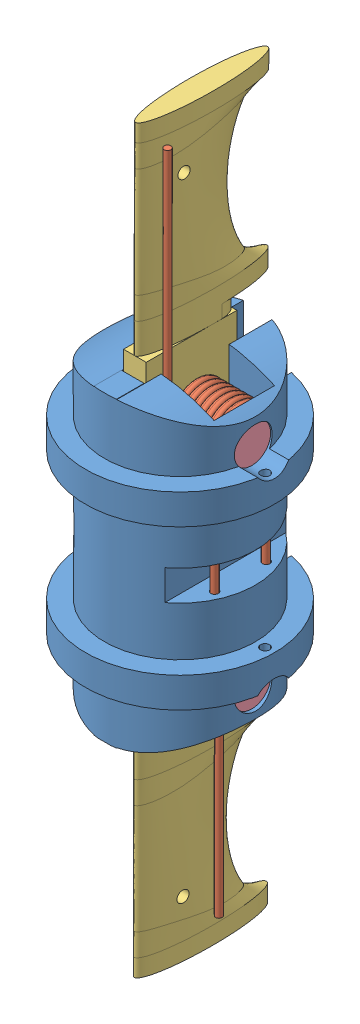
SolidWorks assembly Сборка управления 3, configuration Default. Lengths in mm.
Overall size (25 97.92 24.75).
7 component instances, 4 part files, 14 mates.
Components (placement in the parent):
- Ось Рулей 2-1: Ось Рулей 2 [Default] at (11.2417 23.0929 31.1428) size (25 40 24.75)
- Пружина 1-1: Пружина 1 [Default] at (16.1032 37.0366 31.1428) x (1 0 0) z (0 -1 0) size (7.17 7.86 53.5)
- Пружина 1-2: Пружина 1 [Default] at (16.1032 9.1492 31.1428) x (1 0 0) z (0 1 0) size (7.17 7.86 53.5)
- Плоскость 3-1: Плоскость 3 [Default] at (12.7417 37.0366 31.1428) x (0 0.003497 0.999994) z (-1 0 0) size (17.55 41 3.05)
- Плоскость 3-2: Плоскость 3 [Default] at (9.7417 9.1492 31.1428) x (0 0.001392 0.999999) z (1 0 0) size (17.55 41 3.05)
- ЗАТЫЧКА-1: ЗАТЫЧКА [Default] at (7.7417 37.0366 31.1428) x (0 0.246907 -0.969039) z (1 0 0) size (5 5 13)
- ЗАТЫЧКА-2: ЗАТЫЧКА [Default] at (7.7417 9.1492 31.1428) x (0 0.246907 -0.969039) z (1 0 0) size (5 5 13)
Mates (geometry in assembly coordinates):
- Concentric1: concentric aligned: cylinder of Ось Рулей 2-1 through (7.7417 37.0366 31.1428) axis (1 0 0) radius 2.5; cylinder of Пружина 1-1 through (18.6592 37.0366 31.1428) axis (1 0 0) radius 3
- Concentric2: concentric aligned: cylinder of Ось Рулей 2-1 through (7.7417 9.1492 31.1428) axis (1 0 0) radius 2.5; cylinder of Пружина 1-2 through (18.6592 9.1492 31.1428) axis (1 0 0) radius 3
- Parallel2: parallel aligned: cylinder of Ось Рулей 2-1 through (19.2417 3.0929 27.7279) axis (0 1 0) radius 0.5; cylinder of Пружина 1-2 through (19.2147 9.1492 27.7392) axis (0 1 0) radius 0.4445
- Distance1: distance = 6.75 mm: cylinder of Пружина 1-2 through (12.9917 9.1492 27.7392) axis (0 -1 0) radius 0.4445; plane of Ось Рулей 2-1 through (19.7417 43.7231 35.1428) normal (-1 0 0)
- Parallel3: parallel anti-aligned: cylinder of Ось Рулей 2-1 through (19.2417 3.0929 34.5577) axis (0 1 0) radius 0.5; cylinder of Пружина 1-1 through (19.2147 37.0366 34.5464) axis (0 -1 0) radius 0.4445
- Distance2: distance = 6.75 mm: cylinder of Пружина 1-1 through (12.9917 37.0366 34.5464) axis (0 1 0) radius 0.4445; plane of Ось Рулей 2-1 through (19.7417 22.4628 35.1428) normal (-1 0 0)
- Concentric8: concentric aligned: cylinder of Ось Рулей 2-1 through (7.7417 37.0366 31.1428) axis (1 0 0) radius 2.5; cylinder of Плоскость 3-1 through (9.7417 37.0366 31.1428) axis (1 0 0) radius 2.625
- Coincident1: coincident anti-aligned: plane of Ось Рулей 2-1 through (12.7417 33.0929 21.1428) normal (-1 0 0); plane of Плоскость 3-1 through (12.7417 37.0366 31.1428) normal (1 0 0)
- Concentric9: concentric anti-aligned: cylinder of Ось Рулей 2-1 through (7.7417 9.1492 31.1428) axis (1 0 0) radius 2.5; cylinder of Плоскость 3-2 through (12.7417 9.1492 31.1428) axis (-1 0 0) radius 2.625
- Coincident2: coincident anti-aligned: plane of Ось Рулей 2-1 through (9.7417 13.0929 21.1428) normal (1 0 0); plane of Плоскость 3-2 through (9.7417 9.1492 31.1428) normal (-1 0 0)
- Concentric10: concentric anti-aligned: cylinder of Ось Рулей 2-1 through (7.7417 37.0366 31.1428) axis (1 0 0) radius 2.5; cylinder of ЗАТЫЧКА-1 through (20.7417 37.0366 31.1428) axis (-1 0 0) radius 2.5
- Coincident3: coincident aligned: circle of Ось Рулей 2-1; plane of ЗАТЫЧКА-1 through (7.7417 37.0366 31.1428) normal (-1 0 0)
- Coincident4: coincident anti-aligned: plane of Ось Рулей 2-1 through (7.7417 9.1492 31.1428) normal (1 0 0); plane of ЗАТЫЧКА-2 through (7.7417 9.1492 31.1428) normal (-1 0 0)
- Coincident5: coincident anti-aligned: circle of Ось Рулей 2-1; cylinder of ЗАТЫЧКА-2 through (20.7417 9.1492 31.1428) axis (-1 0 0) radius 2.5
